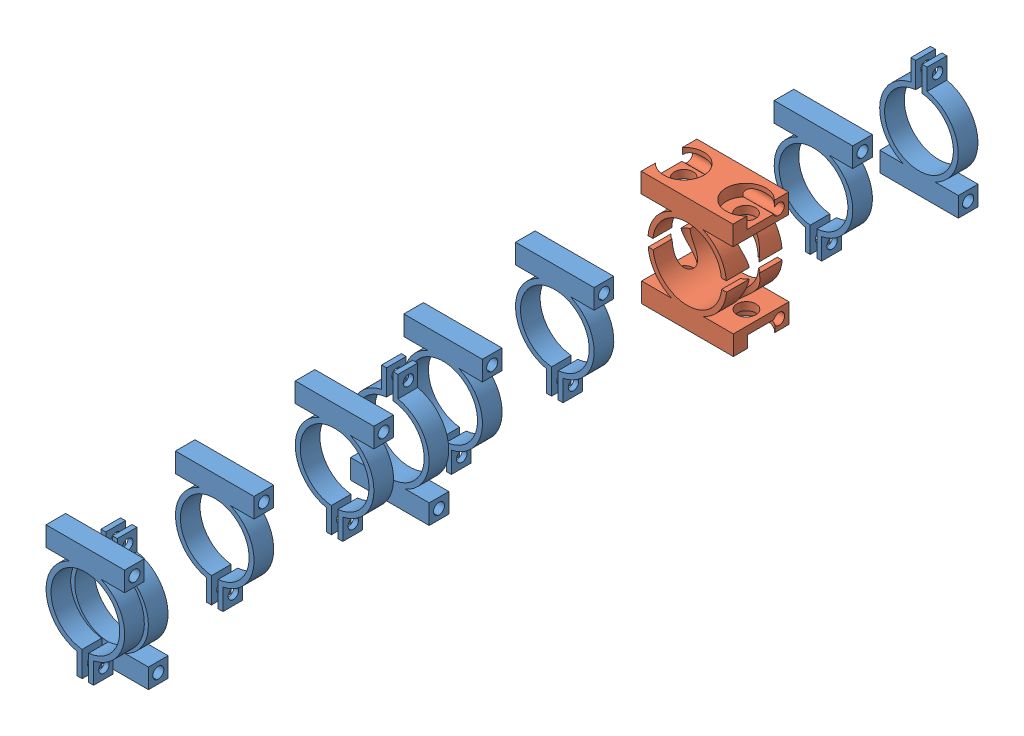
SolidWorks assembly Ensamblaje1, configuration Predeterminado. Lengths in mm.
Overall size (28.78 35.85 261.74).
11 component instances, 2 part files, 0 mates.
Components (placement in the parent):
- acople yagi 1-1: acople yagi 1 [Predeterminado] at (-9.9139 -1.2929 32.2019) size (24.02 35.2 6)
- acople yagi -1: acople yagi  [Predeterminado] at (-9.9533 -1.7318 59.7322) size (28.7 16 17)
- acople yagi -2: acople yagi  [Predeterminado] at (-9.9263 -2.7392 59.6861) x (-1 0 0) z (0 0 1) size (28.7 16 17)
- acople yagi 1-2: acople yagi 1 [Predeterminado] at (-9.6954 -2.2686 0.2077) x (-1 0 0) z (0 0 1) size (24.02 35.2 6)
- acople yagi 1-3: acople yagi 1 [Predeterminado] at (-11.7115 -1.0668 109.3789) size (24.02 35.2 6)
- acople yagi 1-4: acople yagi 1 [Predeterminado] at (-9.908 -1.173 145.2826) size (24.02 35.2 6)
- acople yagi 1-5: acople yagi 1 [Predeterminado] at (-8.9105 -1.3097 179.4351) size (24.02 35.2 6)
- acople yagi 1-6: acople yagi 1 [Predeterminado] at (-8.4324 -1.0825 216.5023) size (24.02 35.2 6)
- acople yagi 1-7: acople yagi 1 [Predeterminado] at (-8.4915 -0.8866 255.9508) size (24.02 35.2 6)
- acople yagi 1-8: acople yagi 1 [Predeterminado] at (-9.2283 -2.2844 162.2524) x (-1 0 0) z (0 0 1) size (24.02 35.2 6)
- acople yagi 1-9: acople yagi 1 [Predeterminado] at (-8.5895 -2.2001 248.6164) x (-1 0 0) z (0 0 1) size (24.02 35.2 6)
